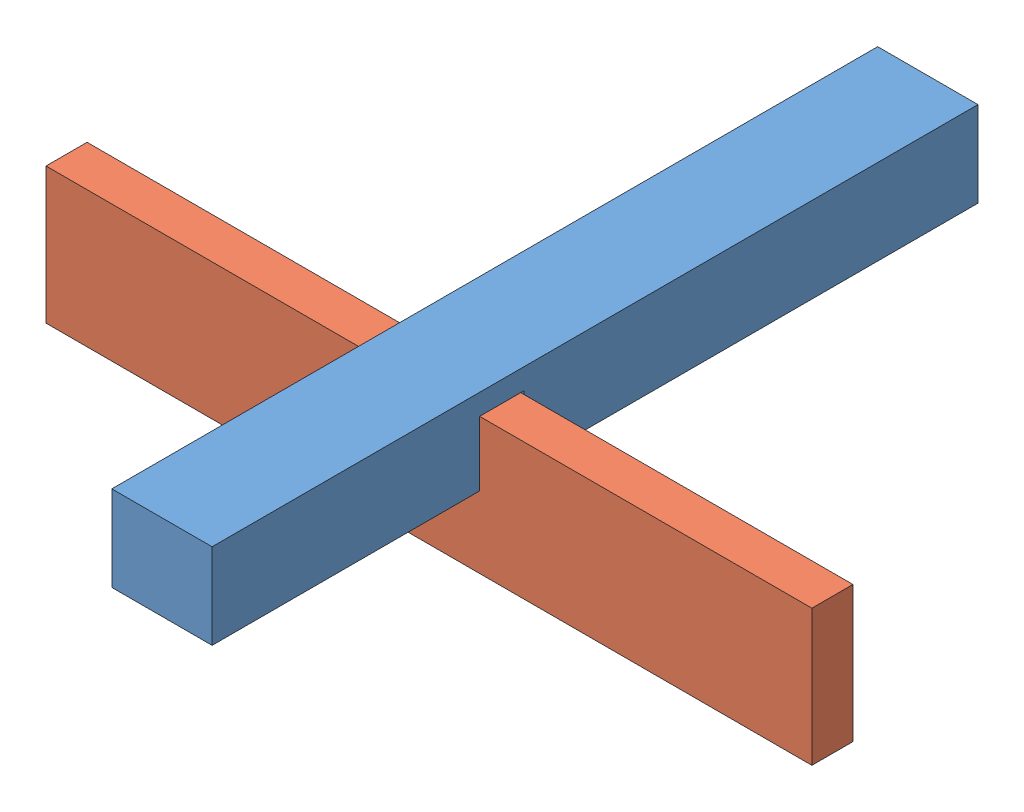
SolidWorks assembly Assemblage2, configuration Défaut. Lengths in mm.
Overall size (888.4 186.05 888.4).
2 component instances, 2 part files, 4 mates.
Components (placement in the parent):
- Pièce6^Assemblage2-1: Pièce6^Assemblage2 [Défaut] at origin size (116.36 99.06 888.4) (virtual)
- Pièce7^Assemblage2-1: Pièce7^Assemblage2 [Défaut] at origin size (888.4 157.89 47.63) (virtual)
Mates (geometry in assembly coordinates):
- Sur place1: in place: plane of ? through (0 0 0) normal (0 0 1); moOrthogonalPlaneRef_w of ? through (0 0 0) normal (0 1 0); plane of ? through (0 0 0) normal (1 0 0); unknown of ?
- Coïncidente1: coincident aligned: plane of Pièce6^Assemblage2-1; plane of assembly
- Coïncidente2: coincident aligned: plane of ? through (0 0 0) normal (0 1 0)
- Coïncidente3: coincident anti-aligned: plane of ? through (0 0 0) normal (1 0 0)
